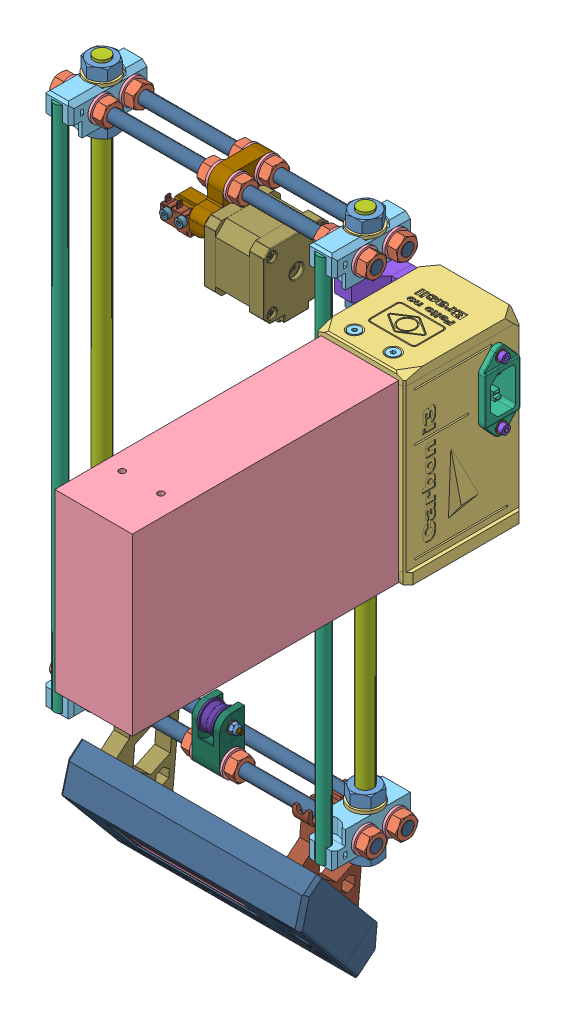
SolidWorks assembly Assembly y-axis, configuration Valor predeterminado. Lengths in mm.
Overall size (295.66 462.65 307.69).
123 component instances, 31 part files, 33 mates.
Components (placement in the parent):
- Assembly y-axis left side-1: Assembly y-axis left side [Valor predeterminado] at (-85 0 0) size (34.2 365 53.48)
  - Assembly y-corners-1: Assembly y-corners [Valor predeterminado] at (-49.2679 151.5842 11.7032) x (-1 0 0) z (0 0 1) size (34.2 40 50.08)
    - Nut DIN 934 - M10-1: Nut DIN 934 - M10 [Valor predeterminado] at (-49.2679 6.8342 8.2968) x (0 -1 0) z (0.866025 0 0.5) size (8 17 19.63)
    - Nut DIN 934 - M8-1: Nut DIN 934 - M8 [Valor predeterminado] at (-63.1179 -10.1658 -1.7032) x (1 0 0) z (0 0.527567 0.849514) size (6.5 13 15.01)
    - Washer DIN 125A - M10-1: Washer DIN 125A - M10 [Valor predeterminado] at (-49.2679 -19.1658 8.2968) x (0 -1 0) z (0.326363 0 0.945245) size (2 20 20)
    - Washer DIN 125A - M8-1: Washer DIN 125A - M8 [Valor predeterminado] at (-40.2679 -10.1658 -1.7032) x (1 0 0) z (0 -0.550558 0.834797) size (1.6 16 16)
    - Washer DIN 125A - M10-2: Washer DIN 125A - M10 [Valor predeterminado] at (-49.2679 2.8342 8.2968) x (0 -1 0) z (0.326363 0 0.945245) size (2 20 20)
    - Washer DIN 125A - M8-2: Washer DIN 125A - M8 [Valor predeterminado] at (-59.8679 -10.1658 -1.7032) x (1 0 0) z (0 0.106248 0.99434) size (1.6 16 16)
    - Nut DIN 934 - M10-2: Nut DIN 934 - M10 [Valor predeterminado] at (-49.2679 -25.1658 8.2968) x (0 -1 0) z (0.866025 0 0.5) size (8 17 19.63)
    - Washer DIN 125A - M8-3: Washer DIN 125A - M8 [Valor predeterminado] at (-59.8679 -10.1658 18.2968) x (1 0 0) z (0 0.258445 0.966026) size (1.6 16 16)
    - Washer DIN 125A - M8-4: Washer DIN 125A - M8 [Valor predeterminado] at (-40.2679 -10.1658 18.2968) x (1 0 0) z (0 -0.676712 0.736248) size (1.6 16 16)
    - Nut DIN 934 - M8-2: Nut DIN 934 - M8 [Valor predeterminado] at (-63.1179 -10.1658 18.2968) x (1 0 0) z (0 0.866025 0.5) size (6.5 13 15.01)
    - Nut DIN 934 - M8-3: Nut DIN 934 - M8 [Valor predeterminado] at (-35.4179 -10.1658 18.2968) x (1 0 0) z (0 0.866025 0.5) size (6.5 13 15.01)
    - Nut DIN 934 - M8-4: Nut DIN 934 - M8 [Valor predeterminado] at (-35.4179 -10.1658 -1.7032) size (6.5 13 15.01)
    - y-corners-2: y-corners [Valor predeterminado] at (-49.2679 0.8342 -11.7032) size (18 22 49)
  - Smooth Rod - 8 x 340-1: Smooth Rod - 8 x 340 [Valor predeterminado] at (0 0 47) x (0.46396 0 0.885856) z (0 -1 0) size (8 8 340)
  - Assembly y-corners-2: Assembly y-corners [Valor predeterminado] at (49.2679 -151.5842 11.7032) size (34.2 40 50.08)
    - Nut DIN 934 - M10-1: Nut DIN 934 - M10 [Valor predeterminado] at (-49.2679 6.8342 8.2968) x (0 -1 0) z (0.866025 0 0.5) size (8 17 19.63)
    - Nut DIN 934 - M8-1: Nut DIN 934 - M8 [Valor predeterminado] at (-63.1179 -10.1658 -1.7032) x (1 0 0) z (0 0.527567 0.849514) size (6.5 13 15.01)
    - Washer DIN 125A - M10-1: Washer DIN 125A - M10 [Valor predeterminado] at (-49.2679 -19.1658 8.2968) x (0 -1 0) z (0.326363 0 0.945245) size (2 20 20)
    - Washer DIN 125A - M8-1: Washer DIN 125A - M8 [Valor predeterminado] at (-40.2679 -10.1658 -1.7032) x (1 0 0) z (0 -0.550558 0.834797) size (1.6 16 16)
    - Washer DIN 125A - M10-2: Washer DIN 125A - M10 [Valor predeterminado] at (-49.2679 2.8342 8.2968) x (0 -1 0) z (0.326363 0 0.945245) size (2 20 20)
    - Washer DIN 125A - M8-2: Washer DIN 125A - M8 [Valor predeterminado] at (-59.8679 -10.1658 -1.7032) x (1 0 0) z (0 0.106248 0.99434) size (1.6 16 16)
    - Nut DIN 934 - M10-2: Nut DIN 934 - M10 [Valor predeterminado] at (-49.2679 -25.1658 8.2968) x (0 -1 0) z (0.866025 0 0.5) size (8 17 19.63)
    - Washer DIN 125A - M8-3: Washer DIN 125A - M8 [Valor predeterminado] at (-59.8679 -10.1658 18.2968) x (1 0 0) z (0 0.258445 0.966026) size (1.6 16 16)
    - Washer DIN 125A - M8-4: Washer DIN 125A - M8 [Valor predeterminado] at (-40.2679 -10.1658 18.2968) x (1 0 0) z (0 -0.676712 0.736248) size (1.6 16 16)
    - Nut DIN 934 - M8-2: Nut DIN 934 - M8 [Valor predeterminado] at (-63.1179 -10.1658 18.2968) x (1 0 0) z (0 0.866025 0.5) size (6.5 13 15.01)
    - Nut DIN 934 - M8-3: Nut DIN 934 - M8 [Valor predeterminado] at (-35.4179 -10.1658 18.2968) x (1 0 0) z (0 0.866025 0.5) size (6.5 13 15.01)
    - Nut DIN 934 - M8-4: Nut DIN 934 - M8 [Valor predeterminado] at (-35.4179 -10.1658 -1.7032) size (6.5 13 15.01)
    - y-corners-2: y-corners [Valor predeterminado] at (-49.2679 0.8342 -11.7032) size (18 22 49)
  - Threaded Rod DIN 975 - M10 x 365-2: Threaded Rod DIN 975 - M10 x 365 [Valor predeterminado] at (0 0 20) x (-0.687133 0 -0.726531) z (0 1 0) size (10 10 365)
- Assembly y-axis right side-1: Assembly y-axis right side [Valor predeterminado] at (85 0 0) size (105.18 380.16 105.18)
  - Smooth Rod - 8 x 340-1: Smooth Rod - 8 x 340 [Valor predeterminado] at (0 0 47) x (0.46396 0 0.885856) z (0 -1 0) size (8 8 340)
  - Assembly y-corners-2: Assembly y-corners [Valor predeterminado] at (49.2679 -151.5842 11.7032) size (34.2 40 50.08)
    - Nut DIN 934 - M10-1: Nut DIN 934 - M10 [Valor predeterminado] at (-49.2679 6.8342 8.2968) x (0 -1 0) z (0.866025 0 0.5) size (8 17 19.63)
    - Nut DIN 934 - M8-1: Nut DIN 934 - M8 [Valor predeterminado] at (-63.1179 -10.1658 -1.7032) x (1 0 0) z (0 0.527567 0.849514) size (6.5 13 15.01)
    - Washer DIN 125A - M10-1: Washer DIN 125A - M10 [Valor predeterminado] at (-49.2679 -19.1658 8.2968) x (0 -1 0) z (0.326363 0 0.945245) size (2 20 20)
    - Washer DIN 125A - M8-1: Washer DIN 125A - M8 [Valor predeterminado] at (-40.2679 -10.1658 -1.7032) x (1 0 0) z (0 -0.550558 0.834797) size (1.6 16 16)
    - Washer DIN 125A - M10-2: Washer DIN 125A - M10 [Valor predeterminado] at (-49.2679 2.8342 8.2968) x (0 -1 0) z (0.326363 0 0.945245) size (2 20 20)
    - Washer DIN 125A - M8-2: Washer DIN 125A - M8 [Valor predeterminado] at (-59.8679 -10.1658 -1.7032) x (1 0 0) z (0 0.106248 0.99434) size (1.6 16 16)
    - Nut DIN 934 - M10-2: Nut DIN 934 - M10 [Valor predeterminado] at (-49.2679 -25.1658 8.2968) x (0 -1 0) z (0.866025 0 0.5) size (8 17 19.63)
    - Washer DIN 125A - M8-3: Washer DIN 125A - M8 [Valor predeterminado] at (-59.8679 -10.1658 18.2968) x (1 0 0) z (0 0.258445 0.966026) size (1.6 16 16)
    - Washer DIN 125A - M8-4: Washer DIN 125A - M8 [Valor predeterminado] at (-40.2679 -10.1658 18.2968) x (1 0 0) z (0 -0.676712 0.736248) size (1.6 16 16)
    - Nut DIN 934 - M8-2: Nut DIN 934 - M8 [Valor predeterminado] at (-63.1179 -10.1658 18.2968) x (1 0 0) z (0 0.866025 0.5) size (6.5 13 15.01)
    - Nut DIN 934 - M8-3: Nut DIN 934 - M8 [Valor predeterminado] at (-35.4179 -10.1658 18.2968) x (1 0 0) z (0 0.866025 0.5) size (6.5 13 15.01)
    - Nut DIN 934 - M8-4: Nut DIN 934 - M8 [Valor predeterminado] at (-35.4179 -10.1658 -1.7032) size (6.5 13 15.01)
    - y-corners-2: y-corners [Valor predeterminado] at (-49.2679 0.8342 -11.7032) size (18 22 49)
  - Threaded Rod DIN 975 - M10 x 365-2: Threaded Rod DIN 975 - M10 x 365 [Valor predeterminado] at (0 0 20) x (0.560623 0 0.828071) z (0 1 0) size (10 10 365)
  - Assembly y-corners + psu-y-part-1: Assembly y-corners + psu-y-part [Valor predeterminado] at (55.3377 186.7114 68.8965) x (-0.405972 -0.883972 0.231905) z (-0.715 0.149183 -0.683022) size (70.09 85.08 72.81)
    - Nut DIN 934 - M10-1: Nut DIN 934 - M10 [Valor predeterminado] at (19.9318 -6.7829 71.4778) x (0.883972 -0.4431 -0.149183) z (0.050052 -0.227561 0.972477) size (8 17 19.63)
    - Nut DIN 934 - M8-1: Nut DIN 934 - M8 [Valor predeterminado] at (36.4951 -12.4723 85.973) x (-0.405972 -0.569176 -0.715) z (0.913882 -0.250711 -0.319317) size (6.5 13 15.01)
    - Washer DIN 125A - M8-1: Washer DIN 125A - M8 [Valor predeterminado] at (39.1642 -1.3807 68.8448) x (0.405972 0.569176 0.715) z (-0.302013 -0.65486 0.692782) size (1.6 16 16)
    - Washer DIN 125A - M10-2: Washer DIN 125A - M10 [Valor predeterminado] at (23.4677 -8.5553 70.881) x (0.883972 -0.4431 -0.149183) z (0.236023 0.147481 0.960491) size (2 20 20)
    - Washer DIN 125A - M8-2: Washer DIN 125A - M8 [Valor predeterminado] at (35.1757 -14.3221 83.6493) x (-0.405972 -0.569176 -0.715) z (0.797091 0.162168 -0.581677) size (1.6 16 16)
    - Washer DIN 125A - M8-3: Washer DIN 125A - M8 [Valor predeterminado] at (26.5691 -26.3887 68.4913) x (0.405972 0.569176 0.715) z (-0.845418 -0.063223 0.530351) size (1.6 16 16)
    - Washer DIN 125A - M8-4: Washer DIN 125A - M8 [Valor predeterminado] at (31.8567 -11.6259 55.9748) x (-0.405972 -0.569176 -0.715) z (0.900505 -0.11575 -0.419157) size (1.6 16 16)
    - Nut DIN 934 - M8-2: Nut DIN 934 - M8 [Valor predeterminado] at (25.2496 -28.2385 66.1675) x (0.405972 0.569176 0.715) z (-0.843078 0.535209 0.05264) size (6.5 13 15.01)
    - Nut DIN 934 - M8-3: Nut DIN 934 - M8 [Valor predeterminado] at (29.8877 -14.3864 52.5071) x (-0.405972 -0.569176 -0.715) z (-0.398683 0.814303 -0.421857) size (6.5 13 15.01)
    - Nut DIN 934 - M8-4: Nut DIN 934 - M8 [Valor predeterminado] at (41.1332 1.3798 72.3126) x (0.405972 0.569176 0.715) z (-0.820941 0.570893 0.011664) size (6.5 13 15.01)
    - psu-y-part-1: psu-y-part [Valor predeterminado] at (45.8824 -41.1595 65.9269) x (-0.405972 -0.569176 -0.715) z (0.231905 0.692604 -0.683022) size (53 38 28)
    - Nut DIN 934 - M10-3: Nut DIN 934 - M10 [Valor predeterminado] at (59.7106 -26.7224 64.7645) x (0.883972 -0.4431 -0.149183) z (-0.416609 -0.601685 -0.681478) size (8 17 19.63)
    - Washer DIN 125A - M10-3: Washer DIN 125A - M10 [Valor predeterminado] at (54.4067 -24.0638 65.6596) x (0.883972 -0.4431 -0.149183) z (0.315015 0.800244 -0.51027) size (2 20 20)
    - y-corners-3: y-corners [Valor predeterminado] at (38.277 -32.1555 81.2595) x (0.405972 0.569176 0.715) z (0.231905 0.692604 -0.683022) size (18 22 49)
- Assembly y-axis back side-2: Assembly y-axis back side [Valor predeterminado] at (0 161.75 2) x (0 -1 0) z (-1 0 0) size (67.29 52.15 205)
  - y-motor-1: y-motor [Valor predeterminado] at (0 -2 -11.25) size (32 48 28)
  - Nut DIN 934 - M8-1: Nut DIN 934 - M8 [Valor predeterminado] at (0 8 -16.1) x (0 0 -1) z (0.866025 0.5 0) size (6.5 13 15.01)
  - Threaded Rod DIN 975 - M8 x 205-1: Threaded Rod DIN 975 - M8 x 205 [Valor predeterminado] at (0 8 0) x (-0.43589 -0.9 0) z (0 0 1) size (8 8 205)
  - Washer DIN 125A - M8-1: Washer DIN 125A - M8 [Valor predeterminado] at (0 8 -11.25) x (0 0 -1) z (0.452123 0.891955 0) size (1.6 16 16)
  - Washer DIN 125A - M8-2: Washer DIN 125A - M8 [Valor predeterminado] at (0 28 0.35) x (0 0 -1) z (0.28551 0.958376 0) size (1.6 16 16)
  - Washer DIN 125A - M8-3: Washer DIN 125A - M8 [Valor predeterminado] at (0 28 -11.25) x (0 0 -1) z (0.655489 0.755205 0) size (1.6 16 16)
  - Washer DIN 125A - M8-4: Washer DIN 125A - M8 [Valor predeterminado] at (0 8 0.35) x (0 0 -1) z (0.269977 0.962867 0) size (1.6 16 16)
  - Nut DIN 934 - M8-2: Nut DIN 934 - M8 [Valor predeterminado] at (0 8 3.6) x (0 0 -1) z (0.866025 0.5 0) size (6.5 13 15.01)
  - Nut DIN 934 - M8-3: Nut DIN 934 - M8 [Valor predeterminado] at (0 28 -16.1) x (0 0 -1) z (0 1 0) size (6.5 13 15.01)
  - Nut DIN 934 - M8-4: Nut DIN 934 - M8 [Valor predeterminado] at (0 28 3.6) x (0 0 -1) z (0.866025 0.5 0) size (6.5 13 15.01)
  - Threaded Rod DIN 975 - M8 x 205-2: Threaded Rod DIN 975 - M8 x 205 [Valor predeterminado] at (0 28 0) x (0.997367 0.072523 0) z (0 0 1) size (8 8 205)
  - Microswitch without leaver - KW11-3Z 5A 250VAC-1: Microswitch without leaver - KW11-3Z 5A 250VAC [Valor predeterminado] at (20.2125 43.2 8.8375) x (0 0 1) z (0 1 0) size (19.85 15.2 6.4)
  - Stepper motor Nema 17-1: Stepper motor Nema 17 [Valor predeterminado] at (24.7456 51.1278 -23.75) x (0 0 -1) z (1 0 0) size (62.01 42.01 48.01)
  - Pulley GT2 20T-1: Pulley GT2 20T [Valor predeterminado] at (29 27 -8.45) x (0 0 1) z (-0.851858 0.523772 0) size (16 16 16)
  - Screw DIN 912 - M3 x 12 --- 12N-1: Screw DIN 912 - M3 x 12 --- 12N [Valor predeterminado] at (18 49.4 13.775) x (0 1 0) z (-0.900551 0 0.434751) size (15 5.5 5.5)
  - Screw DIN 912 - M3 x 12 --- 12N-2: Screw DIN 912 - M3 x 12 --- 12N [Valor predeterminado] at (18 49.4 4.25) x (0 1 0) z (-0.88768 0 0.460461) size (15 5.5 5.5)
  - Screw DIN 912 - M3 x 12 --- 12N-3: Screw DIN 912 - M3 x 12 --- 12N [Valor predeterminado] at (13.5 42.5 -1.25) x (0 0 1) z (0.896632 0.442776 0) size (15 5.5 5.5)
  - Screw DIN 912 - M3 x 12 --- 12N-4: Screw DIN 912 - M3 x 12 --- 12N [Valor predeterminado] at (13.5 11.5 -1.25) x (0 0 1) z (0.896632 0.442776 0) size (15 5.5 5.5)
- Assembly y-axis front side-2: Assembly y-axis front side [Valor predeterminado] at (0 -161.75 22) x (-1 0 0) z (0 0 1) size (205 43.44 24.25)
  - y-idler-1: y-idler [Valor predeterminado] at (9 -20 0) size (18 36 16)
  - Assembly belt-guide + bearing-1: Assembly belt-guide + bearing [Valor predeterminado] at (0 -20 8) size (10.08 24.25 24.25)
    - Radial ball bearing DIN 625 - 623-1: Radial ball bearing DIN 625 - 623 [Valor predeterminado] at origin size (4 10 10)
    - belt-guide-1: belt-guide [Valor predeterminado] at (5.04 0 0) x (0 -0.638719 0.76944) z (-1 0 0) size (17.22 17.22 5)
    - belt-guide-2: belt-guide [Valor predeterminado] at (-5.04 0 0) x (0 -0.984931 0.17295) z (1 0 0) size (17.22 17.22 5)
  - Nut DIN 934 - M8-1: Nut DIN 934 - M8 [Valor predeterminado] at (13.85 0 8) size (6.5 13 15.01)
  - Threaded Rod DIN 975 - M8 x 205-1: Threaded Rod DIN 975 - M8 x 205 [Valor predeterminado] at (0.156 0 8) x (0 -0.74578 -0.666192) z (-1 0 0) size (8 8 205)
  - Washer DIN 125A - M8-1: Washer DIN 125A - M8 [Valor predeterminado] at (9 0 8) x (1 0 0) z (0 0.918544 0.39532) size (1.6 16 16)
  - Washer DIN 125A - M8-2: Washer DIN 125A - M8 [Valor predeterminado] at (-10.6 0 8) x (1 0 0) z (0 0.699031 0.715091) size (1.6 16 16)
  - Nut DIN 934 - M8-2: Nut DIN 934 - M8 [Valor predeterminado] at (-13.85 0 8) x (1 0 0) z (0 0.866025 0.5) size (6.5 13 15.01)
  - Screw DIN 912 - M3 x 25 --- 18N-1: Screw DIN 912 - M3 x 25 --- 18N [Valor predeterminado] at (12.5 -20 8) size (28 5.5 5.5)
  - Nut DIN 985 - M3-1: Nut DIN 985 - M3 [Valor predeterminado] at (-9.5 -20 8) x (1 0 0) z (0 0.5 0.866025) size (4 6.35 5.5)
  - Washer DIN 125A - M3-1: Washer DIN 125A - M3 [Valor predeterminado] at (9 -20 8) x (1 0 0) z (0 -0.048044 0.998845) size (0.5 7 7)
  - Washer DIN 125A - M3-2: Washer DIN 125A - M3 [Valor predeterminado] at (-9.5 -20 8) x (1 0 0) z (0 -0.314993 0.949094) size (0.5 7 7)
- Threaded Rod DIN 975 - M8 x 205-1: Threaded Rod DIN 975 - M8 x 205 [Valor predeterminado] at (0 -161.75 10) x (0 0.91683 -0.399278) z (-1 0 0) size (8 8 205)
- Assembly psu-1: Assembly psu [Valor predeterminado] at (152.7532 113.8192 -58.5) x (0 1 0) z (0 0 1) size (117 80.5 246.9)
  - psu-cover-1: psu-cover [Valor predeterminado] at (-54.1692 22.2532 79.5) size (117 76 75)
  - Power supply - 12V 30A-1: Power supply - 12V 30A [Valor predeterminado] at (-55.1692 -4.7468 218.9) x (0 1 0) z (1 0 0) size (50 215 113)
  - Screw DIN 7991 - M4 x 10 --- 10N-1: Screw DIN 7991 - M4 x 10 --- 10N [Valor predeterminado] at (61.8308 -16.2468 144.5) size (10 7.53 7.53)
  - Screw DIN 7991 - M4 x 10 --- 10N-2: Screw DIN 7991 - M4 x 10 --- 10N [Valor predeterminado] at (61.8308 8.7532 144.5) size (10 7.53 7.53)
  - Screw DIN 7991 - M4 x 10 --- 10N-3: Screw DIN 7991 - M4 x 10 --- 10N [Valor predeterminado] at (-24.1692 25.7532 144.5) x (0 1 0) z (0.450605 0 0.892724) size (10 7.53 7.53)
  - Screw DIN 7991 - M4 x 10 --- 10N-4: Screw DIN 7991 - M4 x 10 --- 10N [Valor predeterminado] at (25.8308 25.7532 144.5) x (0 1 0) z (-0.974607 0 0.223922) size (10 7.53 7.53)
  - AC Power Connector - IEC C14 -1: AC Power Connector - IEC C14  [Valor predeterminado] at (25.8308 -36.7468 95.5) x (1 0 0) z (0 -1 0) size (50 22.4 26.9)
  - Nut DIN 934 - M3-1: Nut DIN 934 - M3 [Valor predeterminado] at (5.8308 -30.7468 95.5) x (0 1 0) z (-0.5 0 0.866025) size (2.4 5.5 6.35)
  - Nut DIN 934 - M3-3: Nut DIN 934 - M3 [Valor predeterminado] at (45.8308 -30.7468 95.5) x (0 1 0) z (-1 0 0) size (2.4 5.5 6.35)
  - Screw DIN 912 - M3 x 10 --- 10N-1: Screw DIN 912 - M3 x 10 --- 10N [Valor predeterminado] at (5.8308 -40.2468 95.5) x (0 -1 0) z (-0.982094 0 -0.188394) size (13 5.5 5.5)
  - Washer DIN 125A - M3-1: Washer DIN 125A - M3 [Valor predeterminado] at (5.8308 -36.7468 95.5) x (0 -1 0) z (0.838676 0 0.544631) size (0.5 7 7)
  - Washer DIN 125A - M3-2: Washer DIN 125A - M3 [Valor predeterminado] at (45.8308 -36.7468 95.5) x (0 -1 0) z (0.065 0 0.997885) size (0.5 7 7)
  - Screw DIN 912 - M3 x 10 --- 10N-2: Screw DIN 912 - M3 x 10 --- 10N [Valor predeterminado] at (45.8308 -40.2468 95.5) x (0 -1 0) z (-0.934431 0 0.356145) size (13 5.5 5.5)
- Washer DIN 125A - M3-1: Washer DIN 125A - M3 [Valor predeterminado] at (120 121.75 27) x (0 0 1) z (-0.987547 0.157322 0) size (0.5 7 7)
- Nut DIN 934 - M3-1: Nut DIN 934 - M3 [Valor predeterminado] at (120 121.75 13.8) x (0 0 1) z (-0.5 0.866025 0) size (2.4 5.5 6.35)
- Screw DIN 912 - M3 x 16 --- 16N-1: Screw DIN 912 - M3 x 16 --- 16N [Valor predeterminado] at (120 141.75 30.5) x (0 0 1) z (-0.901774 0.432207 0) size (19 5.5 5.5)
- Washer DIN 125A - M3-2: Washer DIN 125A - M3 [Valor predeterminado] at (120 141.75 27) x (0 0 1) z (-0.997492 0.070779 0) size (0.5 7 7)
- Nut DIN 934 - M3-2: Nut DIN 934 - M3 [Valor predeterminado] at (120 141.75 13.8) x (0 0 1) z (-1 0 0) size (2.4 5.5 6.35)
- Screw DIN 912 - M3 x 16 --- 16N-2: Screw DIN 912 - M3 x 16 --- 16N [Valor predeterminado] at (120 121.75 30.5) x (0 0 1) z (-0.01292 -0.999917 0) size (19 5.5 5.5)
- Assembly lcd-1: Assembly lcd [Valor predeterminado] at (0 -201.6678 61.8062) x (1 0 0) z (0 0.641012 -0.767531) size (155 93.68 88.88)
  - LCD-cover-1: LCD-cover [Valor predeterminado] at (-0.5 14 0) size (155 70 26)
  - LCD-support-A-1: LCD-support-A [Valor predeterminado] at (65 61.65 21) x (0 0.707107 -0.707107) z (-1 0 0) size (78.2 47.49 10.1)
  - LCD-support-B-1: LCD-support-B [Valor predeterminado] at (-55 61.65 21) x (0 0.707107 -0.707107) z (-1 0 0) size (78.2 47.49 20.05)
  - LCD Smart controller 2004-1: LCD Smart controller 2004 [Valor predeterminado] at (0 31.65 15.25) x (1 0 0) z (0 0 -1) size (150 63 24.8)
Mates (geometry in assembly coordinates):
- Distância2: distance = 170 mm: plane of assembly; plane of assembly; plane of Assembly y-axis right side-1 through (85 0 0) normal (1 0 0); plane of Assembly y-axis left side-1 through (-85 0 0) normal (1 0 0)
- Coincidente6: coincident: plane of assembly through (0 0 0) normal (0 0 1); plane of Assembly y-axis right side-1 through (85 0 0) normal (0 0 1); plane of assembly
- Coincidente7: coincident: plane of assembly through (0 0 0) normal (0 1 0); plane of Assembly y-axis left side-1 through (-85 0 0) normal (0 1 0); plane of assembly
- Simétrico1: symmetric: plane of assembly; plane of assembly; plane of Assembly y-axis left side-1 through (-85 0 0) normal (1 0 0); plane of Assembly y-axis right side-1 through (85 0 0) normal (1 0 0); plane of assembly
- Coincidente8: coincident: plane of assembly through (0 0 0) normal (1 0 0); plane of Assembly y-axis back side-2 through (0 161.75 2) normal (-1 0 0); plane of assembly
- Paralelo2: parallel: plane of assembly through (0 0 0) normal (0 0 1); plane of Assembly y-axis front side-2 through (0 -161.75 22) normal (0 0 1); plane of assembly
- Coincidente10: coincident: plane of assembly through (0 0 0) normal (1 0 0); plane of Assembly y-axis front side-2 through (0 -161.75 22) normal (-1 0 0); plane of assembly
- Coincidente11: coincident: plane of assembly through (0 0 0) normal (1 0 0); plane of Threaded Rod DIN 975 - M8 x 205-1 through (0 -161.75 10) normal (-1 0 0); plane of assembly
- Coincidente12: coincident: plane of assembly; plane of assembly; plane of Assembly y-axis right side-1/Assembly y-corners + psu-y-part-1/psu-y-part-1 through (103 114.75 21) normal (0 0 1); plane of Assembly psu-1/psu-cover-1 through (112.5 113.25 21) normal (0 0 -1)
- Paralelo3: parallel: plane of assembly; plane of assembly; plane of Assembly y-axis right side-1/Assembly y-corners + psu-y-part-1/psu-y-part-1 through (128 114.75 6) normal (1 0 0); plane of Assembly psu-1/psu-cover-1 through (112.5 113.25 21) normal (-1 0 0)
- Coincidente14: coincident: plane of assembly; plane of assembly; plane of Assembly y-axis right side-1/Assembly y-corners + psu-y-part-1/psu-y-part-1 through (120 137.75 6) normal (1 0 0); plane of Assembly psu-1 through (120 113.8192 -58.5) normal (-1 0 0)
- Coincidente15: coincident: plane of assembly; plane of assembly; plane of Assembly y-axis right side-1/Assembly y-corners + psu-y-part-1/psu-y-part-1 through (98 141.75 6) normal (0 1 0); plane of Assembly psu-1 through (152.7532 141.75 -58.5) normal (0 1 0)
- Coincidente18: coincident: plane of assembly; plane of assembly; plane of Assembly psu-1/psu-cover-1 through (112.5 113.25 27) normal (0 0 1); plane of Washer DIN 125A - M3-1 through (120 121.75 27) normal (0 0 -1)
- Coincidente19: coincident: plane of assembly; plane of assembly; plane of Assembly y-axis right side-1/Assembly y-corners + psu-y-part-1/psu-y-part-1 through (120 121.75 15) normal (0 0 -1); plane of Nut DIN 934 - M3-1 through (118.4123 119 15) normal (0 0 1)
- Paralelo4: parallel: line of assembly; plane of assembly; line of Assembly y-axis right side-1/Assembly y-corners + psu-y-part-1/psu-y-part-1 through (123.2 121.75 15) axis (-0.5 0.866025 0); plane of Nut DIN 934 - M3-1 through (123.1754 121.75 15) normal (0.866025 0.5 0)
- Concêntrico10: concentric: cylinder of assembly; cylinder of assembly; cylinder of Screw DIN 912 - M3 x 16 --- 16N-1 through (120 141.75 30.5) axis (0 0 1) radius 1.5; cylinder of Washer DIN 125A - M3-2 through (120 141.75 27.5) axis (0 0 -1) radius 1.6
- Coincidente21: coincident: plane of assembly; plane of assembly; plane of Screw DIN 912 - M3 x 16 --- 16N-1 through (121.1886 144.2299 27.5) normal (0 0 -1); plane of Washer DIN 125A - M3-2 through (120 141.75 27.5) normal (0 0 1)
- Concêntrico11: concentric: cylinder of assembly; cylinder of assembly; cylinder of Assembly y-axis right side-1/Assembly y-corners + psu-y-part-1/psu-y-part-1 through (120 141.75 4) axis (0 0 1) radius 1.6; cylinder of Screw DIN 912 - M3 x 16 --- 16N-1 through (120 141.75 30.5) axis (0 0 1) radius 1.5
- Coincidente23: coincident: plane of assembly; plane of assembly; plane of Assembly psu-1/psu-cover-1 through (112.5 113.25 27) normal (0 0 1); plane of Washer DIN 125A - M3-2 through (120 141.75 27) normal (0 0 -1)
- Concêntrico12: concentric: cylinder of assembly; cylinder of assembly; cylinder of Screw DIN 912 - M3 x 16 --- 16N-1 through (120 141.75 30.5) axis (0 0 1) radius 1.5; cylinder of Nut DIN 934 - M3-2 through (120 141.75 15) axis (0 0 -1) radius 1.25
- Paralelo5: parallel: line of assembly; plane of assembly; line of Assembly y-axis right side-1/Assembly y-corners + psu-y-part-1/psu-y-part-1 through (123.2 141.75 15) axis (-0.5 0.866025 0); plane of Nut DIN 934 - M3-2 through (123.1754 141.75 15) normal (0.866025 0.5 0)
- Coincidente25: coincident: plane of assembly; plane of assembly; plane of Assembly y-axis right side-1/Assembly y-corners + psu-y-part-1/psu-y-part-1 through (120 141.75 15) normal (0 0 -1); plane of Nut DIN 934 - M3-2 through (121.5877 139 15) normal (0 0 1)
- Concêntrico14: concentric: cylinder of assembly; cylinder of assembly; cylinder of Assembly y-axis right side-1/Assembly y-corners + psu-y-part-1/psu-y-part-1 through (120 121.75 4) axis (0 0 1) radius 1.6; cylinder of Screw DIN 912 - M3 x 16 --- 16N-2 through (120 121.75 30.5) axis (0 0 1) radius 1.5
- Coincidente26: coincident: plane of assembly; plane of assembly; plane of Washer DIN 125A - M3-1 through (120 121.75 27.5) normal (0 0 1); plane of Screw DIN 912 - M3 x 16 --- 16N-2 through (117.2502 121.7855 27.5) normal (0 0 -1)
- Concêntrico15: concentric: cylinder of assembly; cylinder of assembly; cylinder of Nut DIN 934 - M3-1 through (120 121.75 15) axis (0 0 -1) radius 1.25; cylinder of Screw DIN 912 - M3 x 16 --- 16N-2 through (120 121.75 30.5) axis (0 0 1) radius 1.5
- Concêntrico16: concentric: cylinder of Assembly y-axis front side-2/Threaded Rod DIN 975 - M8 x 205-1 through (102.344 -161.75 30) axis (-1 0 0) radius 4; cylinder of Assembly lcd-1/LCD-support-B-1 through (-54 -161.75 30) axis (-1 0 0) radius 4.2
- Coincidente28: coincident: plane of assembly through (0 0 0) normal (1 0 0); plane of Assembly lcd-1 through (0 -201.6678 61.8062) normal (1 0 0); plane of assembly
- Concêntrico17: concentric: cylinder of assembly; cylinder of assembly; cylinder of Washer DIN 125A - M3-1 through (120 121.75 27.5) axis (0 0 -1) radius 1.6; cylinder of Screw DIN 912 - M3 x 16 --- 16N-2 through (120 121.75 30.5) axis (0 0 1) radius 1.5
- Concêntrico19: concentric: cylinder of Assembly y-axis left side-1/Assembly y-corners-2/Nut DIN 934 - M8-2 through (-95.6 -161.75 30) axis (-1 0 0) radius 3.4; cylinder of Assembly y-axis front side-2/Threaded Rod DIN 975 - M8 x 205-1 through (102.344 -161.75 30) axis (-1 0 0) radius 4
- Concêntrico20: concentric: cylinder of assembly; cylinder of assembly; cylinder of Assembly y-axis left side-1/Assembly y-corners-2/Nut DIN 934 - M8-1 through (-95.6 -161.75 10) axis (-1 0 0) radius 3.4; cylinder of Threaded Rod DIN 975 - M8 x 205-1 through (-102.5 -161.75 10) axis (1 0 0) radius 4
- Concêntrico21: concentric: cylinder of Assembly y-axis right side-1/Assembly y-corners-2/Nut DIN 934 - M8-3 through (102.1 -161.75 30) axis (-1 0 0) radius 3.4; cylinder of Assembly y-axis front side-2/Threaded Rod DIN 975 - M8 x 205-1 through (102.344 -161.75 30) axis (-1 0 0) radius 4
- Concêntrico22: concentric: cylinder of Assembly y-axis left side-1/Assembly y-corners-1/Nut DIN 934 - M8-2 through (-74.4 161.75 30) axis (1 0 0) radius 3.4; cylinder of Assembly y-axis back side-2/Threaded Rod DIN 975 - M8 x 205-2 through (-102.5 161.75 30) axis (1 0 0) radius 4
- Concêntrico23: concentric: cylinder of Assembly y-axis left side-1/Assembly y-corners-1/Nut DIN 934 - M8-4 through (-102.1 161.75 10) axis (1 0 0) radius 3.4; cylinder of Assembly y-axis back side-2/Threaded Rod DIN 975 - M8 x 205-1 through (-102.5 161.75 10) axis (1 0 0) radius 4
